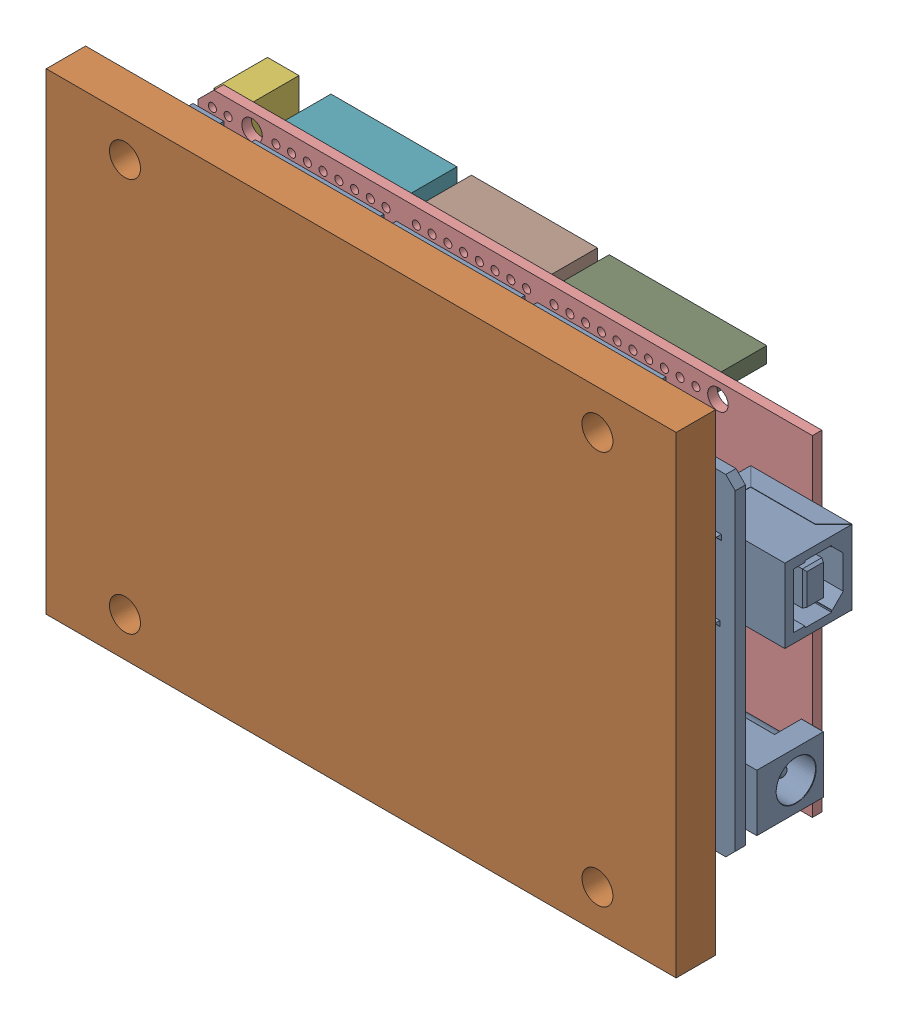
SolidWorks assembly MegaAssembly, configuration Default. Lengths in mm.
Overall size (107.95 76.2 32.13).
3 component instances, 3 part files, 7 mates.
Components (placement in the parent):
- ArduinoMega-2: ArduinoMega [Default] at (-16.7528 4.2196 8.6161) size (107.95 53.42 12.95)
- MegaStand-1: MegaStand [Default] at (-16.7528 4.2196 19.7921) x (0 1 0) z (-1 0 0) size (76.2 12.7 101.6)
- Arduino Mega Protoboard-2: Arduino Mega Protoboard [Default] at (34.0472 -22.4504 -2.9409) x (-1 0 0) z (0 -1 0) size (101.6 10.16 53.34)
Mates (geometry in assembly coordinates):
- Width1: width anti-aligned: plane of MegaStand-1 through (-67.5528 -33.8804 13.4421) normal (0 -1 0); plane of MegaStand-1 through (-67.5528 42.3196 13.4421) normal (0 1 0); plane of ArduinoMega-2 through (-67.5528 30.9277 10.2671) normal (0 1 0); plane of ArduinoMega-2 through (-67.5528 -22.4885 10.2671) normal (0 -1 0)
- Parallel2: parallel anti-aligned: plane of ArduinoMega-2 through (34.0472 -22.4885 10.2671) normal (0 0 1); plane of MegaStand-1 through (-16.7528 4.2196 13.4421) normal (0 0 -1)
- Width2: width anti-aligned: plane of MegaStand-1 through (-67.5528 -33.8804 13.4421) normal (-1 0 0); plane of MegaStand-1 through (34.0472 -33.8804 13.4421) normal (1 0 0); plane of ArduinoMega-2 through (34.0472 30.9277 10.2671) normal (1 0 0); plane of ArduinoMega-2 through (-67.5528 30.9277 10.2671) normal (-1 0 0)
- Coincident1: coincident anti-aligned: plane of ArduinoMega-2 through (34.0472 -22.4885 10.2671) normal (0 0 1); plane of MegaStand-1 through (-16.7528 4.2196 10.2671) normal (0 0 -1)
- Coincident4: coincident: plane of ArduinoMega-2 through (34.0472 30.9277 10.2671) normal (1 0 0); plane of Arduino Mega Protoboard-2 through (34.0472 -22.4504 -3.7029) normal (1 0 0)
- Coincident5: coincident: plane of ArduinoMega-2 through (24.0904 9.7187 -2.1789) normal (0 0 -1); plane of Arduino Mega Protoboard-2 through (34.0472 -22.4504 -2.1789) normal (0 0 1)
- Width3: width anti-aligned: plane of Arduino Mega Protoboard-2 through (34.0472 30.8896 -3.7029) normal (0 1 0); plane of ArduinoMega-2 through (34.0472 -22.4504 -3.7029) normal (0 -1 0); plane of Arduino Mega Protoboard-2 through (-67.5528 -22.4885 10.2671) normal (0 -1 0); plane of ArduinoMega-2 through (-67.5528 30.9277 10.2671) normal (0 1 0)
